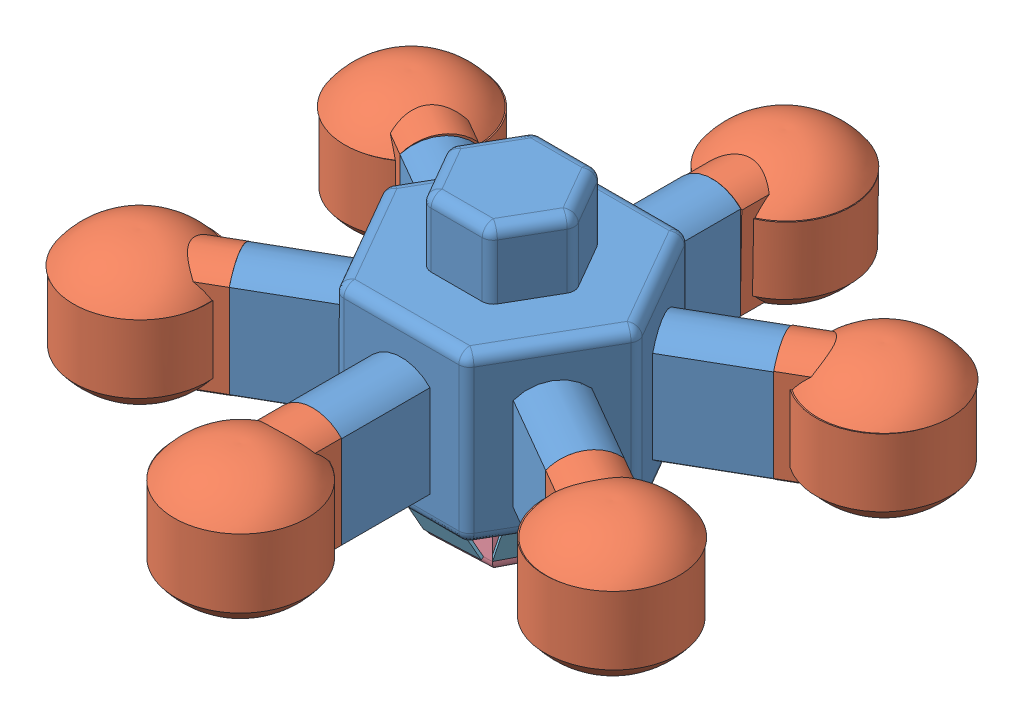
SolidWorks assembly xdesign lander, configuration Default. Lengths in mm.
Overall size (58290.42 27000 67100.91).
15 component instances, 5 part files, 42 mates.
Components (placement in the parent):
- xdesign main room-1: xdesign main room [Default] at (17116.1202 16025.9425 22914.4842) size (33778.75 21000 36001.07)
- xdesign small room-1: xdesign small room [Default] at (-4105.7674 12428.8628 35157.0942) x (0.286101 0.017238 -0.958044) z (0.958187 0 0.286144) size (12939.16 12030.58 12691.46)
- xdesign small room-2: xdesign small room [Default] at (-4098.0369 12546.6341 10658.4838) x (0.972741 0.017238 -0.231251) z (0.231285 0 0.972886) size (12939.16 12030.58 12691.46)
- xdesign small room-3: xdesign small room [Default] at (17032.2113 12424.6233 -1585.5339) x (0.686835 0.005395 0.726793) z (-0.726793 0.012529 0.686742) size (12939.16 12030.58 12691.46)
- xdesign small room-4: xdesign small room [Default] at (38330.2772 12422.7084 35170.4845) x (-0.972741 0.017238 0.231251) z (-0.231285 0 -0.972886) size (12939.16 12030.58 12691.46)
- xdesign small room-5: xdesign small room [Default] at (38339.2594 12458.9761 10674.0431) x (-0.286101 0.017238 0.958044) z (-0.958187 0 -0.286144) size (12939.16 12030.58 12691.46)
- xdesign small room-6: xdesign small room [Default] at (17109.191 12458.9719 47414.4832) x (-0.68664 0.017238 -0.726793) z (0.726901 0 -0.686742) size (12939.16 12030.58 12691.46)
- Xdesign door-1: Xdesign door [Default] at (17116.1202 15525.9425 22914.4842) x (-0.979114 0 0.203312) z (-0.203312 0 -0.979114) size (6000 500 6000)
- SmallBox-1: SmallBox [Default] at (17116.1202 10025.9425 22914.4842) x (-0.991432 0 -0.130625) z (0.130625 0 -0.991432) size (11370.75 6000 10852.27)
- Thing-1: Thing [Default] at (17004.3307 13191.006 29175.4409) x (0.999034 0 -0.043934) z (0.038048 -0.5 0.865189) size (5000 5000 250)
- Thing-2: Thing [Default] at (11485.7253 13091.2894 26045.2768) x (-0.537565 0 -0.843222) z (0.737499 0.48481 -0.470165) size (5000 5000 250)
- Thing-3: Thing [Default] at (11557.7923 13066.006 19587.2823) x (0.461469 0 -0.887156) z (0.7683 0.5 0.399644) size (5000 5000 250)
- Thing-4: Thing [Default] at (17218.3976 13066.006 16437.2301) x (0.999034 0 -0.043934) z (0.038048 0.5 0.865189) size (5000 5000 250)
- Thing-5: Thing [Default] at (22178.3543 13191.006 19228.5837) x (0.537565 0 0.843222) z (-0.730252 0.5 0.465545) size (5000 5000 250)
- Thing-6: Thing [Default] at (22290.2981 13316.006 26041.864) x (0.461469 0 -0.887156) z (0.7683 -0.5 0.399644) size (5000 5000 250)
Mates (geometry in assembly coordinates):
- Coincident1: coincident anti-aligned: plane of xdesign main room-1 through (1528.0542 24354.4432 31915.1629) normal (-0.86613 0 0.499819); plane of xdesign small room-1 through (1524.9781 24360.583 31909.8324) normal (0.86613 0 -0.499819)
- Coincident2: coincident anti-aligned: circle of xdesign main room-1; circle of xdesign small room-1
- Coincident3: coincident anti-aligned: plane of xdesign main room-1 through (1464.4506 24354.4285 14023.9173) normal (-0.865921 0 -0.500181); plane of xdesign small room-2 through (1529.547 24478.3542 13911.2215) normal (0.865921 0 0.500181)
- Coincident5: coincident aligned: plane of xdesign main room-1 through (227.3725 18575.3474 29661.2268) normal (-0.499819 0 -0.86613); plane of xdesign small room-1 through (227.3725 26956.7354 29661.2268) normal (-0.499819 0 -0.86613)
- Parallel1: parallel aligned: plane of xdesign main room-1 through (2828.0938 18693.1187 11663.1593) normal (0.500181 0 -0.865921); plane of xdesign small room-2 through (2828.0938 27074.5067 11663.1593) normal (0.500181 0 -0.865921)
- Coincident7: coincident anti-aligned: line of xdesign main room-1 through (2828.0938 26813.5572 11663.1593) axis (0 -1 0); line of xdesign small room-2 through (2828.0938 18693.1187 11663.1593) axis (0 1 0)
- Parallel3: parallel anti-aligned: cylinder of xdesign main room-1 through (1464.4506 24354.4285 14023.9173) axis (0.865921 0 0.500181) radius 3671.514; cylinder of xdesign small room-2 through (1529.547 24478.3542 13911.2215) axis (-0.865921 0 -0.500181) radius 3671.514
- Coincident12: coincident anti-aligned: line of xdesign main room-1 through (231.0002 18693.1187 16159.2837) axis (0.865921 0 0.500181); line of xdesign small room-2 through (231.0002 18693.1187 16159.2837) axis (-0.865921 0 -0.500181)
- Coincident13: coincident anti-aligned: plane of xdesign main room-1 through (17179.7667 24355.0752 4914.4971) normal (0.000209 0 -1); plane of xdesign small room-3 through (17234.7442 24354.6013 4914.5086) normal (-0.000209 0 1)
- Concentric4: concentric anti-aligned: cylinder of xdesign main room-1 through (17179.7667 21165.9921 4914.4971) axis (-0.000209 0 1) radius 3671.514; cylinder of xdesign small room-3 through (17179.7667 21165.9921 4914.4971) axis (0.000209 0 -1) radius 3671.514
- Parallel4: parallel anti-aligned: line of xdesign main room-1 through (19775.9191 26950.313 4915.0405) axis (-0.000209 0 1); line of xdesign small room-3 through (19875.2665 26905.6121 4915.0613) axis (0.000209 0 -1)
- Coincident15: coincident anti-aligned: plane of xdesign main room-1 through (32702.6933 24354.4285 31917.7468) normal (0.865921 0 0.500181); plane of xdesign small room-4 through (32702.6933 24354.4285 31917.7468) normal (-0.865921 0 -0.500181)
- Concentric5: concentric anti-aligned: cylinder of xdesign main room-1 through (32702.6933 24354.4285 31917.7468) axis (-0.865921 0 -0.500181) radius 3671.514; cylinder of xdesign small room-4 through (32702.6933 24354.4285 31917.7468) axis (0.865921 0 0.500181) radius 3671.514
- Coincident16: coincident anti-aligned: line of xdesign main room-1 through (31404.1465 18569.193 34165.809) axis (-0.865921 0 -0.500181); line of xdesign small room-4 through (31404.1465 18569.193 34165.809) axis (0.865921 0 0.500181)
- Coincident17: coincident anti-aligned: plane of xdesign main room-1 through (32708.5139 24390.6962 13921.3049) normal (0.86613 0 -0.499819); plane of xdesign small room-5 through (32708.5139 24390.6962 13921.3049) normal (-0.86613 0 0.499819)
- Concentric6: concentric anti-aligned: cylinder of xdesign main room-1 through (32708.5139 24390.6962 13921.3049) axis (-0.86613 0 0.499819) radius 3635.2505; cylinder of xdesign small room-5 through (32708.5139 24390.6962 13921.3049) axis (0.86613 0 -0.499819) radius 3671.514
- Coincident18: coincident anti-aligned: line of xdesign main room-1 through (31410.9084 18605.4607 11672.6993) axis (-0.86613 0 0.499819); line of xdesign small room-5 through (31410.9084 18605.4607 11672.6993) axis (0.86613 0 -0.499819)
- Coincident19: coincident anti-aligned: plane of xdesign main room-1 through (17112.3526 24390.692 40914.4838) normal (-0.000209 0 1); plane of xdesign small room-6 through (17112.3526 24390.692 40914.4838) normal (0.000209 0 -1)
- Concentric8: concentric anti-aligned: cylinder of xdesign main room-1 through (17112.3526 21201.6089 40914.4838) axis (0.000209 0 -1) radius 3671.514; cylinder of xdesign small room-6 through (17112.3526 21201.6089 40914.4838) axis (-0.000209 0 1) radius 3671.514
- Concentric9: concentric anti-aligned: cylinder of xdesign main room-1 through (17112.3526 24390.692 40914.4838) axis (0.000209 0 -1) radius 3635.2505; cylinder of xdesign small room-6 through (17112.3526 24390.692 40914.4838) axis (-0.000209 0 1) radius 3671.514
- Coincident20: coincident anti-aligned: plane of xdesign main room-1 through (17116.1202 16025.9425 22914.4842) normal (0 -1 0); plane of Xdesign door-1 through (17116.1202 16025.9425 22914.4842) normal (0 1 0)
- Coincident21: coincident anti-aligned: circle of xdesign main room-1; circle of Xdesign door-1
- Coincident22: coincident anti-aligned: plane of Xdesign door-1 through (17116.1202 15525.9425 22914.4842) normal (0 -1 0); plane of SmallBox-1 through (17116.1202 15525.9425 22914.4842) normal (0 1 0)
- Coincident23: coincident aligned: circle of Xdesign door-1; circle of SmallBox-1
- Coincident25: coincident aligned: line of SmallBox-1 through (14451.827 11025.9425 28036.4833) axis (0.999034 0 -0.043934); line of Thing-1 through (14451.827 11025.9425 28036.4833) axis (0.999034 0 -0.043934)
- Angle2: planar angle = 0.523599 rad aligned: line of Thing-1 through (14561.6624 15356.0695 30534.0694) axis (-0.021967 -0.866025 -0.499517); line of SmallBox-1 through (14451.827 16025.9425 28036.4833) axis (0 -1 0)
- Coincident27: coincident: point of SmallBox-1; point of Thing-1
- Coincident28: coincident anti-aligned: line of SmallBox-1 through (11348.1922 11025.9425 23168.1381) axis (0.537565 0 0.843222); line of Thing-2 through (14036.0188 11025.9425 27384.2487) axis (-0.537565 0 -0.843222)
- Coincident29: coincident: point of SmallBox-1; point of Thing-2
- Angle3: planar angle = 0.506145 rad anti-aligned: line of Thing-2 through (11348.1922 11025.9425 23168.1381) axis (-0.408802 0.87462 0.260617); line of SmallBox-1 through (11348.1922 16025.9425 23168.1381) axis (0 -1 0)
- Coincident31: coincident anti-aligned: line of SmallBox-1 through (14012.4854 11025.9425 18046.139) axis (-0.461469 0 0.887156); line of Thing-3 through (11705.1398 11025.9425 22481.9204) axis (0.461469 0 -0.887156)
- Coincident32: coincident: point of SmallBox-1; point of Thing-3
- Angle4: planar angle = 0.523599 rad anti-aligned: line of Thing-3 through (14012.4854 11025.9425 18046.139) axis (-0.443578 0.866025 -0.230735); line of SmallBox-1 through (14012.4854 16025.9425 18046.139) axis (0 -1 0)
- Coincident34: coincident anti-aligned: line of SmallBox-1 through (19780.4134 11025.9425 17792.485) axis (-0.999034 0 0.043934); line of Thing-4 through (14785.2412 11025.9425 18012.1558) axis (0.999034 0 -0.043934)
- Coincident35: coincident: point of SmallBox-1; point of Thing-4
- Angle5: planar angle = 0.523599 rad anti-aligned: line of Thing-4 through (19780.4134 11025.9425 17792.485) axis (-0.021967 0.866025 -0.499517); line of SmallBox-1 through (19780.4134 16025.9425 17792.485) axis (0 -1 0)
- Coincident37: coincident anti-aligned: line of SmallBox-1 through (22884.0481 11025.9425 22660.8302) axis (-0.537565 0 -0.843222); line of Thing-5 through (19780.4134 11025.9425 17792.485) axis (0.537565 0 0.843222)
- Coincident38: coincident: point of Thing-4; point of Thing-5
- Angle7: planar angle = 0.523599 rad aligned: line of Thing-5 through (21705.9057 15481.0695 16564.958) axis (-0.421611 -0.866025 0.268783); line of SmallBox-1 through (19780.4134 16025.9425 17792.485) axis (0 -1 0)
- Coincident41: coincident aligned: line of SmallBox-1 through (20219.7549 11025.9425 27782.8293) axis (0.461469 0 -0.887156); line of Thing-6 through (20219.7549 11025.9425 27782.8293) axis (0.461469 0 -0.887156)
- Coincident42: coincident: point of SmallBox-1; point of Thing-6
- Angle8: planar angle = 0.523599 rad aligned: line of Thing-6 through (22245.5707 15481.0695 28836.5911) axis (-0.443578 -0.866025 -0.230735); line of SmallBox-1 through (20219.7549 16025.9425 27782.8293) axis (0 -1 0)
